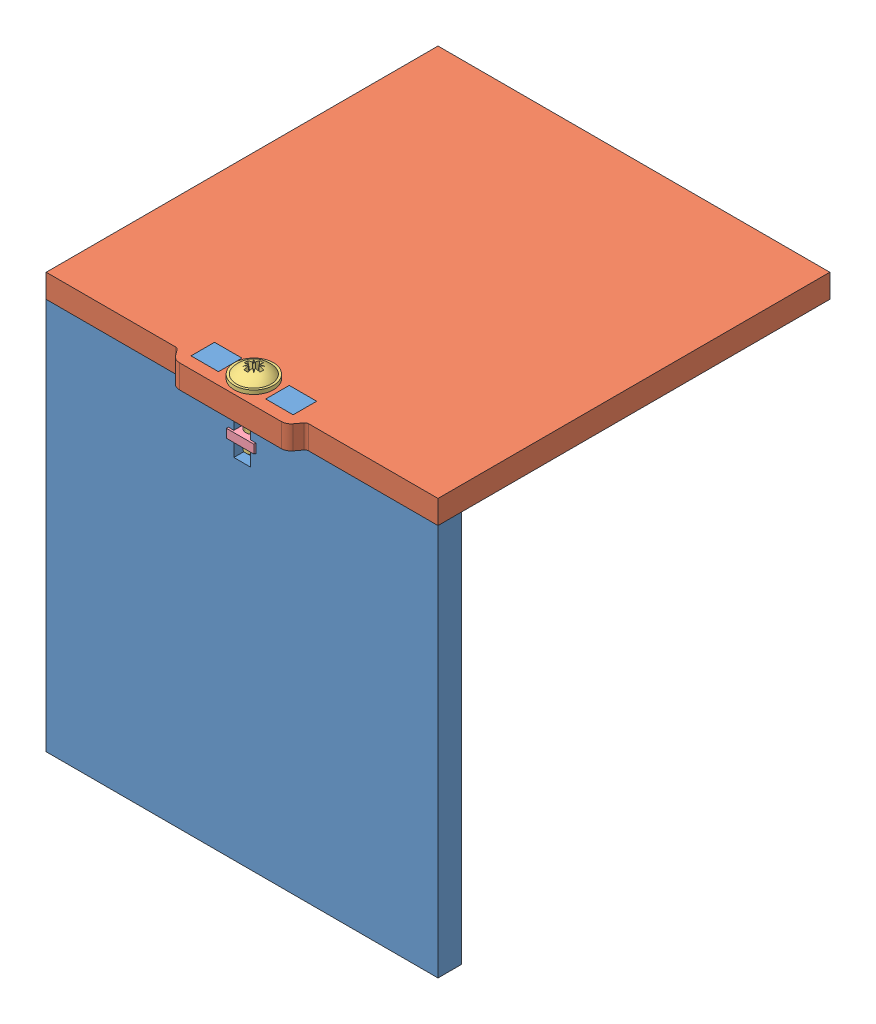
SolidWorks assembly auto_mount_m4_16, configuration По умолчанию. Lengths in mm.
Overall size (100 108.96 113.56).
4 component instances, 4 part files, 9 mates.
Components (placement in the parent):
- plywood_test_m4_16-1: plywood_test_m4_16 [По умолчанию] at (51.7183 54.318 64.1682) size (100 106 6)
- plywood_test2_m4_16-2: plywood_test2_m4_16 [По умолчанию] at (51.7183 104.318 20.1682) x (-1 0 0) z (0 1 0) size (100 103 6)
- DIN967-1: DIN967 [M4х16] at (51.7183 113.368 67.1682) x (0 -1 0) z (0 0 1) size (18.96 34 34.42)
- din 562 m4-1: din 562 m4 [По умолчанию] at (51.7181 99.318 67.1664) x (1 0 0) z (0 -1 0) size (7 7 2.2)
Mates (geometry in assembly coordinates):
- Совпадение1: coincident aligned: plane of plywood_test-1 through (51.7183 54.318 70.1682) normal (0 0 1); plane of plywood_test2-2 through (101.7183 110.318 70.1682) normal (0 0 1)
- Совпадение2: coincident anti-aligned: plane of plywood_test-1 through (1.7183 104.318 70.1682) normal (0 1 0); plane of plywood_test2-2 through (51.7183 104.318 20.1682) normal (0 -1 0)
- Совпадение3: coincident aligned: plane of plywood_test-1 through (101.7183 4.318 70.1682) normal (1 0 0); plane of plywood_test2-2 through (101.7183 110.318 -29.8318) normal (1 0 0)
- Совпадение5: coincident anti-aligned: plane of plywood_test2-2 through (51.7183 110.318 20.1682) normal (0 1 0); plane of DIN967-1 through (53.7183 110.318 67.1682) normal (0 -1 0)
- Совпадение6: coincident: plane of plywood_test-1 through (51.7183 54.318 67.1682) normal (0 0 1); line of DIN967-1 through (51.7183 119.2763 67.1682) axis (0 -1 0)
- Совпадение7: coincident: line of DIN967-1 through (51.7183 119.2763 67.1682) axis (0 -1 0)
- Концентричный1: concentric anti-aligned: cylinder of DIN967-1 through (51.7183 119.718 67.1682) axis (0 1 0) radius 2; cylinder of din 562 m4-1 through (51.7183 99.318 67.1682) axis (0 -1 0) radius 2
- Совпадение8: coincident anti-aligned: plane of plywood_test-1 through (49.6183 99.318 64.1682) normal (0 -1 0); plane of din 562 m4-1 through (51.7181 99.318 67.1664) normal (0 1 0)
- Совпадение9: coincident anti-aligned: plane of plywood_test-1 through (51.7183 54.318 70.1682) normal (0 0 1); plane of DIN967-1 through (51.7183 113.368 70.1682) normal (0 0 -1)
